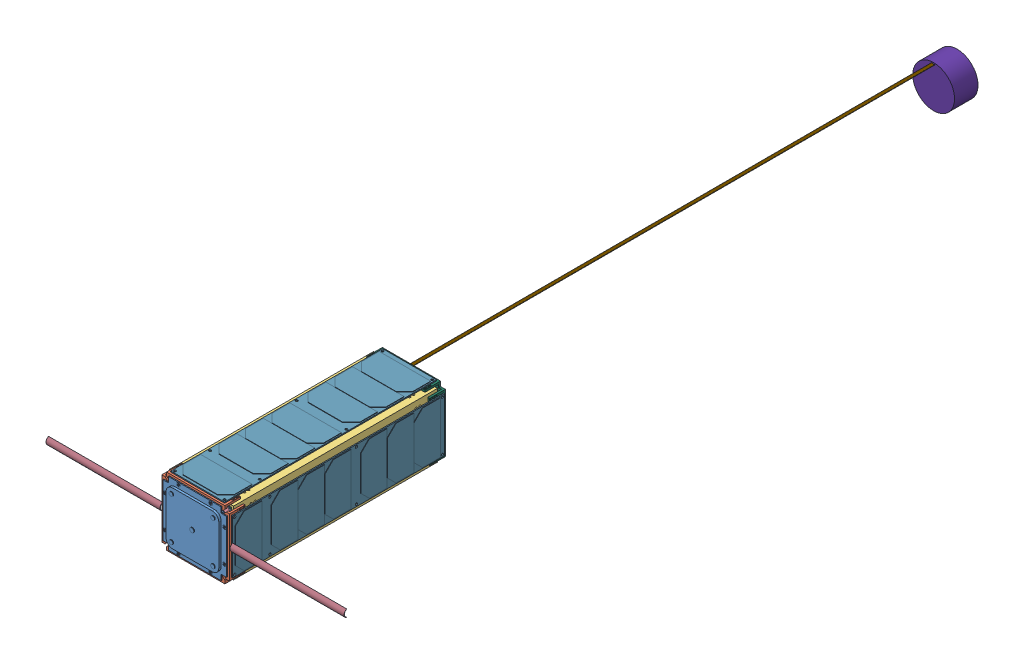
SolidWorks assembly RADIO Deconstructed, configuration Default. Lengths in mm.
Overall size (457.2 117.23 1173).
77 component instances, 18 part files, 145 mates.
Components (placement in the parent):
- Nanocom Antenna-1: Nanocom Antenna [Default] at (54.7327 27.087 80.9297) size (98 98 11)
- Top Sipport-1: Top Sipport [Default] at (83.9034 50.4516 80.9297) x (0 -1 0) z (0 0 -1) size (89.4 11 24)
- Top Sipport-2: Top Sipport [Default] at (-15.8818 37.5538 80.9297) x (0 1 0) z (0 0 -1) size (89.4 11 24)
- Top Sipport-3: Top Sipport [Default] at (27.5619 93.8953 80.9297) x (1 0 0) z (0 0 -1) size (89.4 11 24)
- Top Sipport-4: Top Sipport [Default] at (40.4598 -5.8899 80.9297) x (-1 0 0) z (0 0 -1) size (89.4 11 24)
- Support-1: Support [Default] at (-14.9892 90.3455 -221.7132) x (0 -1 0) z (1 0 0) size (18 313 15)
- Support-2: Support [Default] at (-12.332 -4.9973 -221.7132) x (1 0 0) z (0 1 0) size (18 313 15)
- Support-3: Support [Default] at (80.3537 93.0027 -221.7132) x (-1 0 0) z (0 -1 0) size (18 313 15)
- Support-4: Support [Default] at (83.0108 -2.3402 -221.7132) x (0 1 0) z (-1 0 0) size (18 313 15)
- Top Plate2-1: Top Plate2 [Default] at (13.317 21.6849 56.9297) x (-1 0 0) z (0 0 -1) size (92 92 23)
- Nut-1: Nut [Default] at (-1.4892 79.5027 56.9297) size (11.55 10 5.32)
- Nut-2: Nut [Default] at (69.5108 8.5027 56.9297) x (0.821931 0.569587 0) z (0 0 1) size (11.55 10 5.32)
- Nut-3: Nut [Default] at (69.5108 79.5027 56.9297) size (11.55 10 5.32)
- Nut-4: Nut [Default] at (-1.4892 8.5027 56.9297) size (11.55 10 5.32)
- Threaded Rod2-1: Threaded Rod2 [Default] at (69.5108 8.5027 -231.0703) size (6.4 7.01 294.26)
- Threaded Rod2-2: Threaded Rod2 [Default] at (-1.4892 8.5027 -231.0703) size (6.4 7.01 294.26)
- Threaded Rod2-3: Threaded Rod2 [Default] at (-1.4892 79.5027 -231.0703) size (6.4 7.01 294.26)
- Threaded Rod2-4: Threaded Rod2 [Default] at (69.5108 79.5027 -231.0703) size (6.4 7.01 294.26)
- Mid Plate-1: Mid Plate [Default] at (4.649 54.0261 25.9297) size (86 86 3)
- Nut-5: Nut [Default] at (-1.4892 8.5027 20.9297) x (0.999286 -0.037791 0) z (0 0 1) size (11.55 10 5.32)
- Nut-6: Nut [Default] at (-1.4892 8.5027 28.9297) size (11.55 10 5.32)
- Nut-7: Nut [Default] at (69.5108 8.5027 28.9297) size (11.55 10 5.32)
- Nut-8: Nut [Default] at (69.5108 8.5027 20.9297) x (0.921379 0.388666 0) z (0 0 1) size (11.55 10 5.32)
- Nut-9: Nut [Default] at (69.5108 79.5027 28.9297) size (11.55 10 5.32)
- Nut-10: Nut [Default] at (-1.4892 79.5027 28.9297) size (11.55 10 5.32)
- Nut-11: Nut [Default] at (69.5108 79.5027 20.9297) x (0.963517 0.267648 0) z (0 0 1) size (11.55 10 5.32)
- Nut-12: Nut [Default] at (-1.4892 79.5027 20.9297) x (0.997929 0.06432 0) z (0 0 1) size (11.55 10 5.32)
- SDR-1: SDR [Default] at (37.1692 34.198 30.9297) size (65 40 16.8)
- TTC Radio-1: TTC Radio [Default] at (48.3672 78.5027 28.9297) x (0 1 0) z (0 0 1) size (19.7 16 5)
- Raspberry Pi-1: Raspberry Pi [Default] at (63.5108 49.6464 -55.0703) size (66 30.48 5)
- TTC Circuit-1: TTC Circuit [Default] at (24.4431 25.9578 10.9297) size (80 50 10)
- Battery-1: Battery [Default] at (21.7415 31.358 -37.0703) size (70.1 42.59 38.1)
- Tape Antenna-3: Tape Antenna [Default] at (-194.5892 44.2096 75.6458) x (0 -0.999378 0.035253) z (1 0 0) size (11.67 4.21 175)
- Tape Antenna-4: Tape Antenna [Default] at (262.6108 43.4652 75.6178) x (0 0.999544 0.030207) z (-1 0 0) size (11.67 4.21 175)
- Mid Plate-2: Mid Plate [Default] at (4.649 54.0261 7.9297) size (86 86 3)
- Nut-13: Nut [Default] at (-1.4892 8.5027 10.9297) size (11.55 10 5.32)
- Nut-14: Nut [Default] at (69.5108 79.5027 10.9297) size (11.55 10 5.32)
- Nut-15: Nut [Default] at (-1.4892 8.5027 2.9297) size (11.55 10 5.32)
- Nut-16: Nut [Default] at (-1.4892 79.5027 10.9297) size (11.55 10 5.32)
- Nut-17: Nut [Default] at (-1.4892 79.5027 2.9297) size (11.55 10 5.32)
- Nut-18: Nut [Default] at (69.5108 8.5027 2.9297) size (11.55 10 5.32)
- Nut-19: Nut [Default] at (69.5108 8.5027 10.9297) size (11.55 10 5.32)
- Nut-20: Nut [Default] at (69.5108 79.5027 2.9297) size (11.55 10 5.32)
- Mid Plate-3: Mid Plate [Default] at (4.649 54.0261 -40.0703) size (86 86 3)
- Nut-21: Nut [Default] at (69.5108 79.5027 -37.0703) size (11.55 10 5.32)
- Nut-22: Nut [Default] at (-1.4892 8.5027 -40.0703) x (-0.923728 -0.383049 0) z (0 0 -1) size (11.55 10 5.32)
- Nut-23: Nut [Default] at (-1.4892 79.5027 -40.0703) x (-0.923728 -0.383049 0) z (0 0 -1) size (11.55 10 5.32)
- Nut-24: Nut [Default] at (69.5108 8.5027 -37.0703) size (11.55 10 5.32)
- Nut-25: Nut [Default] at (69.5108 79.5027 -40.0703) x (-0.923728 -0.383049 0) z (0 0 -1) size (11.55 10 5.32)
- Nut-26: Nut [Default] at (69.5108 8.5027 -40.0703) x (-0.923728 -0.383049 0) z (0 0 -1) size (11.55 10 5.32)
- Nut-27: Nut [Default] at (-1.4892 8.5027 -37.0703) size (11.55 10 5.32)
- Nut-28: Nut [Default] at (-1.4892 79.5027 -37.0703) size (11.55 10 5.32)
- Nut-29: Nut [Default] at (-1.4892 8.5027 -63.0703) size (11.55 10 5.32)
- Nut-30: Nut [Default] at (69.5108 79.5027 -63.0703) size (11.55 10 5.32)
- Nut-31: Nut [Default] at (69.5108 8.5027 -63.0703) size (11.55 10 5.32)
- Nut-32: Nut [Default] at (-1.4892 8.5027 -55.0703) size (11.55 10 5.32)
- Nut-33: Nut [Default] at (-1.4892 79.5027 -55.0703) size (11.55 10 5.32)
- Nut-34: Nut [Default] at (69.5108 8.5027 -55.0703) size (11.55 10 5.32)
- Nut-35: Nut [Default] at (-1.4892 79.5027 -63.0703) size (11.55 10 5.32)
- Nut-36: Nut [Default] at (69.5108 79.5027 -55.0703) size (11.55 10 5.32)
- Mid Plate-4: Mid Plate [Default] at (4.649 54.0261 -58.0703) size (86 86 3)
- Top Plate2-2: Top Plate2 [Default] at (54.7047 21.6849 -226.0703) size (92 92 23)
- Nut-37: Nut [Default] at (69.5108 8.5027 -226.0703) x (-0.923728 -0.383049 0) z (0 0 -1) size (11.55 10 5.32)
- Nut-38: Nut [Default] at (69.5108 79.5027 -226.0703) x (-0.923728 -0.383049 0) z (0 0 -1) size (11.55 10 5.32)
- Nut-39: Nut [Default] at (-1.4892 8.5027 -226.0703) x (-0.923728 -0.383049 0) z (0 0 -1) size (11.55 10 5.32)
- Nut-40: Nut [Default] at (-1.4892 79.5027 -226.0703) x (-0.923728 -0.383049 0) z (0 0 -1) size (11.55 10 5.32)
- 3U Panel-1: 3U Panel [Default] at (-17.9892 -8.6653 1.9441) x (0 -1 0) z (-1 0 0) size (82.6 325 2.3)
- 3U Panel-5: 3U Panel [Default] at (86.6788 -7.9973 1.9441) x (1 0 0) z (0 -1 0) size (82.6 325 2.3)
- 3U Panel-6: 3U Panel [Default] at (86.0108 96.6707 1.9441) x (0 1 0) z (1 0 0) size (82.6 325 2.3)
- 3U Panel-7: 3U Panel [Default] at (-18.6571 96.0027 1.9441) x (-1 0 0) z (0 1 0) size (82.6 325 2.3)
- Top Support Solar Panel-1: Top Support Solar Panel [Default] at (27.5619 -3.8899 -250.0703) size (89.4 13 24)
- Top Support Solar Panel-2: Top Support Solar Panel [Default] at (81.9034 37.5538 -250.0703) x (0 1 0) z (0 0 1) size (89.4 13 24)
- Top Support Solar Panel-3: Top Support Solar Panel [Default] at (40.4598 91.8953 -250.0703) x (-1 0 0) z (0 0 1) size (89.4 13 24)
- Top Support Solar Panel-4: Top Support Solar Panel [Default] at (-13.8818 50.4516 -250.0703) x (0 -1 0) z (0 0 1) size (89.4 13 24)
- 1U Panel-1: 1U Panel [Default] at (10.1282 49.1305 -250.0703) x (-1 0 0) z (0 0 -1) size (98 98 2.3)
- Mass-1: Mass [Default] at (35.0433 65.173 -1086.0703) x (-0.924883 -0.380251 0) z (0 0 1) size (64 64 36)
- Deployed Boom-1: Deployed Boom [Default] at (35.2379 68.8164 -1050.0703) x (0 0 1) z (-0.999908 -0.013572 0) size (800 1.49 5.53)
Mates (geometry in assembly coordinates):
- Coincident1: coincident: circle of Nanocom Antenna-1; circle of Top Sipport-4
- Coincident2: coincident: circle of Nanocom Antenna-1; circle of Top Sipport-4
- Coincident3: coincident: circle of Nanocom Antenna-1; circle of Top Sipport-2
- Coincident4: coincident: circle of Nanocom Antenna-1; circle of Top Sipport-2
- Coincident5: coincident: circle of Nanocom Antenna-1; circle of Top Sipport-3
- Coincident6: coincident: circle of Nanocom Antenna-1; circle of Top Sipport-3
- Coincident7: coincident: circle of Nanocom Antenna-1; circle of Top Sipport-1
- Coincident8: coincident: circle of Nanocom Antenna-1; circle of Top Sipport-1
- Coincident9: coincident: circle of Top Sipport-2; circle of Support-1
- Coincident10: coincident: circle of Top Sipport-3; circle of Support-1
- Coincident11: coincident: circle of Top Sipport-3; circle of Support-3
- Coincident12: coincident: circle of Top Sipport-1; circle of Support-3
- Coincident13: coincident: circle of Top Sipport-2; circle of Support-2
- Coincident14: coincident: circle of Top Sipport-4; circle of Support-2
- Coincident16: coincident: circle of Top Sipport-4; circle of Support-4
- Coincident17: coincident: circle of Top Sipport-1; circle of Support-4
- Coincident20: coincident: circle of Support-1; circle of Top Plate2-1
- Coincident21: coincident: circle of Support-2; circle of Top Plate2-1
- Coincident22: coincident: circle of Top Plate2-1; circle of Nut-3
- Coincident23: coincident: circle of Top Plate2-1; circle of Nut-1
- Coincident24: coincident: circle of Top Plate2-1; circle of Nut-4
- Coincident25: coincident: circle of Top Plate2-1; circle of Nut-2
- Concentric1: concentric: circle of Top Plate2-1; circle of Threaded Rod2-1
- Coincident26: coincident: plane of Nut-2 through (69.5108 8.5027 61.9297) normal (0 0 1); plane of Threaded Rod2-1 through (69.5108 8.5027 61.9297) normal (0 0 1)
- Concentric2: concentric: circle of Top Plate2-1; circle of Threaded Rod2-4
- Coincident27: coincident: plane of Nut-3 through (69.5108 79.5027 61.9297) normal (0 0 1); plane of Threaded Rod2-4 through (69.5108 79.5027 61.9297) normal (0 0 1)
- Concentric3: concentric: circle of Top Plate2-1; circle of Threaded Rod2-2
- Coincident28: coincident: plane of Nut-4 through (-1.4892 8.5027 61.9297) normal (0 0 1); plane of Threaded Rod2-2 through (-1.4892 8.5027 61.9297) normal (0 0 1)
- Concentric4: concentric: circle of Top Plate2-1; circle of Threaded Rod2-3
- Coincident29: coincident: plane of Nut-1 through (-1.4892 79.5027 61.9297) normal (0 0 1); plane of Threaded Rod2-3 through (-1.4892 79.5027 61.9297) normal (0 0 1)
- Concentric5: concentric: circle of Threaded Rod2-4; circle of Mid Plate-1
- Concentric6: concentric: circle of Threaded Rod2-2; circle of Mid Plate-1
- Concentric7: concentric: circle of Threaded Rod2-2; circle of Nut-6
- Coincident30: coincident: plane of Mid Plate-1 through (4.649 54.0261 28.9297) normal (0 0 1); plane of Nut-6 through (-1.4892 8.5027 28.9297) normal (0 0 -1)
- Concentric8: concentric: circle of Threaded Rod2-2; circle of Nut-5
- Coincident31: coincident: plane of Mid Plate-1 through (4.649 54.0261 25.9297) normal (0 0 -1); plane of Nut-5 through (-1.4892 8.5027 25.9297) normal (0 0 1)
- Concentric9: concentric: circle of Threaded Rod2-1; circle of Nut-7
- Coincident32: coincident: plane of Mid Plate-1 through (4.649 54.0261 28.9297) normal (0 0 1); plane of Nut-7 through (69.5108 8.5027 28.9297) normal (0 0 -1)
- Concentric10: concentric: circle of Threaded Rod2-1; circle of Nut-8
- Coincident33: coincident: plane of Mid Plate-1 through (4.649 54.0261 25.9297) normal (0 0 -1); plane of Nut-8 through (69.5108 8.5027 25.9297) normal (0 0 1)
- Concentric11: concentric: circle of Threaded Rod2-4; circle of Nut-9
- Coincident34: coincident: plane of Mid Plate-1 through (4.649 54.0261 28.9297) normal (0 0 1); plane of Nut-9 through (69.5108 79.5027 28.9297) normal (0 0 -1)
- Concentric12: concentric: circle of Threaded Rod2-3; circle of Nut-10
- Coincident35: coincident: plane of Mid Plate-1 through (4.649 54.0261 28.9297) normal (0 0 1); plane of Nut-10 through (-1.4892 79.5027 28.9297) normal (0 0 -1)
- Concentric13: concentric: circle of Threaded Rod2-4; circle of Nut-11
- Coincident36: coincident: plane of Mid Plate-1 through (4.649 54.0261 25.9297) normal (0 0 -1); plane of Nut-11 through (69.5108 79.5027 25.9297) normal (0 0 1)
- Concentric14: concentric: circle of Threaded Rod2-3; circle of Nut-12
- Coincident37: coincident: plane of Mid Plate-1 through (4.649 54.0261 25.9297) normal (0 0 -1); plane of Nut-12 through (-1.4892 79.5027 25.9297) normal (0 0 1)
- Distance1: distance = 25 mm: plane of Mid Plate-1 through (4.649 54.0261 28.9297) normal (0 0 1); plane of Top Plate2-1 through (13.317 21.6849 53.9297) normal (0 0 -1)
- Coincident39: coincident: plane of Mid Plate-1 through (4.649 54.0261 28.9297) normal (0 0 1); plane of SDR-1 through (37.1692 34.198 28.9297) normal (0 0 -1)
- Distance4: distance = 12 mm: line of SDR-1 through (65.0108 16.0027 28.9297) axis (0 1 0); line of Mid Plate-1 through (77.0108 4.0027 28.9297) axis (0 1 0)
- Distance5: distance = 15 mm: line of SDR-1 through (0.0108 16.0027 28.9297) axis (1 0 0); line of Mid Plate-1 through (-5.9892 1.0027 28.9297) axis (1 0 0)
- Coincident46: coincident: plane of Mid Plate-1 through (4.649 54.0261 28.9297) normal (0 0 1); plane of TTC Radio-1 through (48.3672 78.5027 28.9297) normal (0 0 -1)
- Distance8: distance = 20 mm: plane of TTC Radio-1 through (57.0108 78.5027 30.9297) normal (1 0 0); plane of Mid Plate-1 through (77.0108 4.0027 28.9297) normal (1 0 0)
- Distance9: distance = 5 mm: plane of TTC Radio-1 through (48.3672 82.0027 30.9297) normal (0 1 0); line of Mid Plate-1 through (74.0108 87.0027 28.9297) axis (-1 0 0)
- Coincident53: coincident: plane of TTC Circuit-1 through (24.4431 25.9578 10.9297) normal (0 0 -1); plane of Mid Plate-2 through (4.649 54.0261 10.9297) normal (0 0 1)
- Distance10: distance = 5 mm: line of TTC Circuit-1 through (-4.4066 66.0027 12.9297) axis (0 -1 0); line of Mid Plate-2 through (-8.9892 84.0027 10.9297) axis (0 -1 0)
- Distance13: distance = 21.095 mm: line of TTC Circuit-1 through (75.5934 66.0027 12.9297) axis (-1 0 0); line of Mid Plate-2 through (74.0108 87.0027 10.9297) axis (-1 0 0)
- Concentric16: concentric: circle of Threaded Rod2-2; circle of Mid Plate-2
- Concentric18: concentric: circle of Threaded Rod2-4; circle of Mid Plate-2
- Concentric19: concentric: circle of Threaded Rod2-4; circle of Nut-14
- Coincident59: coincident: plane of Mid Plate-2 through (4.649 54.0261 10.9297) normal (0 0 1); plane of Nut-14 through (69.5108 79.5027 10.9297) normal (0 0 -1)
- Concentric20: concentric: circle of Threaded Rod2-4; circle of Nut-20
- Coincident60: coincident: plane of Mid Plate-2 through (4.649 54.0261 7.9297) normal (0 0 -1); plane of Nut-20 through (69.5108 79.5027 7.9297) normal (0 0 1)
- Concentric21: concentric: circle of Threaded Rod2-1; circle of Nut-19
- Coincident61: coincident: plane of Mid Plate-2 through (4.649 54.0261 10.9297) normal (0 0 1); plane of Nut-19 through (69.5108 8.5027 10.9297) normal (0 0 -1)
- Concentric22: concentric: circle of Threaded Rod2-1; circle of Nut-18
- Coincident62: coincident: plane of Mid Plate-2 through (4.649 54.0261 7.9297) normal (0 0 -1); plane of Nut-18 through (69.5108 8.5027 7.9297) normal (0 0 1)
- Concentric23: concentric: circle of Threaded Rod2-2; circle of Nut-13
- Coincident63: coincident: plane of Mid Plate-2 through (4.649 54.0261 10.9297) normal (0 0 1); plane of Nut-13 through (-1.4892 8.5027 10.9297) normal (0 0 -1)
- Concentric24: concentric: circle of Threaded Rod2-2; circle of Nut-15
- Coincident64: coincident: plane of Mid Plate-2 through (4.649 54.0261 7.9297) normal (0 0 -1); plane of Nut-15 through (-1.4892 8.5027 7.9297) normal (0 0 1)
- Concentric25: concentric: circle of Threaded Rod2-3; circle of Nut-16
- Coincident65: coincident: plane of Mid Plate-2 through (4.649 54.0261 10.9297) normal (0 0 1); plane of Nut-16 through (-1.4892 79.5027 10.9297) normal (0 0 -1)
- Concentric26: concentric: circle of Threaded Rod2-3; circle of Nut-17
- Coincident66: coincident: plane of Mid Plate-2 through (4.649 54.0261 7.9297) normal (0 0 -1); plane of Nut-17 through (-1.4892 79.5027 7.9297) normal (0 0 1)
- Distance14: distance = 15 mm: plane of Mid Plate-2 through (4.649 54.0261 10.9297) normal (0 0 1); plane of Mid Plate-1 through (4.649 54.0261 25.9297) normal (0 0 -1)
- Coincident68: coincident: circle of Mid Plate-3; circle of Nut-21
- Coincident69: coincident: circle of Mid Plate-3; circle of Nut-24
- Coincident70: coincident: circle of Mid Plate-3; circle of Nut-27
- Coincident71: coincident: circle of Mid Plate-3; circle of Nut-28
- Coincident72: coincident: circle of Mid Plate-3; circle of Nut-25
- Coincident73: coincident: circle of Mid Plate-3; circle of Nut-23
- Coincident74: coincident: circle of Mid Plate-3; circle of Nut-22
- Coincident76: coincident: circle of Mid Plate-3; circle of Nut-26
- Coincident77: coincident: plane of Battery-1 through (21.7415 31.358 -37.0703) normal (0 0 -1); plane of Mid Plate-3 through (4.649 54.0261 -37.0703) normal (0 0 1)
- Distance16: distance = 30 mm: line of Battery-1 through (57.8687 57.4223 -32.0703) axis (-1 0 0); line of Mid Plate-3 through (74.0108 87.0027 -37.0703) axis (-1 0 0)
- Distance17: distance = 15 mm: line of Battery-1 through (62.8687 24.8323 -32.0703) axis (0 1 0); line of Mid Plate-3 through (77.0108 4.0027 -37.0703) axis (0 1 0)
- Concentric27: concentric: circle of Threaded Rod2-2; circle of Nut-27
- Concentric28: concentric: circle of Threaded Rod2-4; circle of Nut-21
- Distance18: distance = 45 mm: plane of Mid Plate-3 through (4.649 54.0261 -37.0703) normal (0 0 1); plane of Mid Plate-2 through (4.649 54.0261 7.9297) normal (0 0 -1)
- Coincident83: coincident: plane of Raspberry Pi-1 through (63.5108 49.6464 -55.0703) normal (0 0 -1); plane of Mid Plate-4 through (4.649 54.0261 -55.0703) normal (0 0 1)
- Distance19: distance = 30 mm: line of Raspberry Pi-1 through (67.0108 57.0027 -55.0703) axis (-1 0 0); line of Mid Plate-4 through (74.0108 87.0027 -55.0703) axis (-1 0 0)
- Distance20: distance = 10 mm: line of Raspberry Pi-1 through (67.0108 26.5227 -55.0703) axis (0 1 0); line of Mid Plate-4 through (77.0108 4.0027 -55.0703) axis (0 1 0)
- Concentric29: concentric: circle of Nut-29; circle of Mid Plate-4
- Coincident87: coincident: plane of Nut-29 through (-1.4892 8.5027 -58.0703) normal (0 0 1); plane of Mid Plate-4 through (4.649 54.0261 -58.0703) normal (0 0 -1)
- Concentric30: concentric: circle of Nut-31; circle of Mid Plate-4
- Coincident89: coincident: plane of Nut-31 through (69.5108 8.5027 -58.0703) normal (0 0 1); plane of Mid Plate-4 through (4.649 54.0261 -58.0703) normal (0 0 -1)
- Concentric31: concentric: circle of Nut-30; circle of Mid Plate-4
- Coincident91: coincident: plane of Nut-30 through (69.5108 79.5027 -58.0703) normal (0 0 1); plane of Mid Plate-4 through (4.649 54.0261 -58.0703) normal (0 0 -1)
- Concentric32: concentric: circle of Nut-35; circle of Mid Plate-4
- Coincident93: coincident: plane of Nut-35 through (-1.4892 79.5027 -58.0703) normal (0 0 1); plane of Mid Plate-4 through (4.649 54.0261 -58.0703) normal (0 0 -1)
- Coincident94: coincident: circle of Nut-33; circle of Mid Plate-4
- Coincident95: coincident: circle of Nut-32; circle of Mid Plate-4
- Coincident96: coincident: circle of Nut-36; circle of Mid Plate-4
- Coincident97: coincident: circle of Nut-34; circle of Mid Plate-4
- Concentric33: concentric: circle of Threaded Rod2-2; circle of Nut-29
- Concentric34: concentric: circle of Threaded Rod2-3; circle of Nut-35
- Distance21: distance = 15 mm: plane of Mid Plate-4 through (4.649 54.0261 -55.0703) normal (0 0 1); plane of Mid Plate-3 through (4.649 54.0261 -40.0703) normal (0 0 -1)
- Coincident100: coincident: circle of Top Plate2-2; circle of Nut-37
- Coincident101: coincident: circle of Top Plate2-2; circle of Nut-39
- Coincident102: coincident: circle of Top Plate2-2; circle of Nut-38
- Coincident103: coincident: circle of Top Plate2-2; circle of Nut-40
- Concentric35: concentric: circle of Threaded Rod2-3; circle of Top Plate2-2
- Concentric36: concentric: circle of Threaded Rod2-4; circle of Top Plate2-2
- Coincident104: coincident: plane of Threaded Rod2-4 through (69.5108 79.5027 -231.0703) normal (0 0 -1); plane of Nut-38 through (69.5108 79.5027 -231.0703) normal (0 0 -1)
- Coincident123: coincident: circle of Top Sipport-2; circle of 3U Panel-1
- Coincident124: coincident: circle of Top Sipport-2; circle of 3U Panel-1
- Coincident125: coincident: circle of Top Sipport-4; circle of 3U Panel-5
- Coincident126: coincident: circle of Top Sipport-4; circle of 3U Panel-5
- Coincident127: coincident: circle of Top Sipport-3; circle of 3U Panel-7
- Coincident128: coincident: circle of Top Sipport-3; circle of 3U Panel-7
- Coincident129: coincident: circle of Top Sipport-1; circle of 3U Panel-6
- Coincident130: coincident: circle of Top Sipport-1; circle of 3U Panel-6
- Coincident131: coincident: point of Tape Antenna-4; line of 3U Panel-6 through (87.6108 85.3027 77.9297) axis (0 -1 0)
- Coincident132: coincident: point of Tape Antenna-4; line of 3U Panel-6 through (87.6108 85.3027 77.9297) axis (0 -1 0)
- Coincident137: coincident: point of Tape Antenna-3; line of 3U Panel-1 through (-19.5892 2.7027 77.9297) axis (0 1 0)
- Coincident138: coincident: point of Tape Antenna-3; line of 3U Panel-1 through (-19.5892 2.7027 77.9297) axis (0 1 0)
- Coincident140: coincident: circle of 3U Panel-6; circle of Top Support Solar Panel-2
- Coincident141: coincident: circle of 3U Panel-6; circle of Top Support Solar Panel-2
- Coincident142: coincident: circle of 3U Panel-5; circle of Top Support Solar Panel-1
- Coincident143: coincident: circle of 3U Panel-5; circle of Top Support Solar Panel-1
- Coincident144: coincident: circle of 3U Panel-1; circle of Top Support Solar Panel-4
- Coincident145: coincident: circle of 3U Panel-1; circle of Top Support Solar Panel-4
- Coincident146: coincident: circle of 3U Panel-7; circle of Top Support Solar Panel-3
- Coincident147: coincident: circle of 3U Panel-7; circle of Top Support Solar Panel-3
- Coincident148: coincident: circle of Top Support Solar Panel-3; circle of 1U Panel-1
- Coincident149: coincident: circle of Top Support Solar Panel-1; circle of 1U Panel-1
- Parallel21: parallel: line of Nanocom Antenna-1 through (74.5108 93.0027 82.4297) axis (-1 0 0); line of Tape Antenna-3 through (-19.5892 50.0375 78.0383) axis (-1 0 0); line of Nanocom Antenna-1; line of Tape Antenna-4; line of Support-1; line of Deployed Boom-1
- Parallel22: parallel: line of Nanocom Antenna-1 through (74.5108 93.0027 82.4297) axis (-1 0 0); line of Tape Antenna-4 through (87.6108 49.3257 77.9297) axis (1 0 0)
- Parallel23: parallel: line of Support-1 through (-14.9892 93.0027 -241.0703) axis (0 0 1); line of Deployed Boom-1 through (37.3663 96.0027 -250.0703) axis (0 0 -1)
- Coincident157: coincident: line of Top Support Solar Panel-3 through (78.7108 96.0027 -250.0703) axis (-1 0 0); point of Deployed Boom-1
- Coincident158: coincident: line of Top Support Solar Panel-3 through (78.7108 96.0027 -250.0703) axis (-1 0 0); point of Deployed Boom-1
- Distance25: distance = 43 mm: point of Deployed Boom-1; point of Top Support Solar Panel-3
- Coincident160: coincident: plane of Mass-1 through (35.0433 65.173 -1050.0703) normal (0 0 1); plane of Deployed Boom-1 through (34.8386 98.2368 -1050.0703) normal (0 0 -1)
